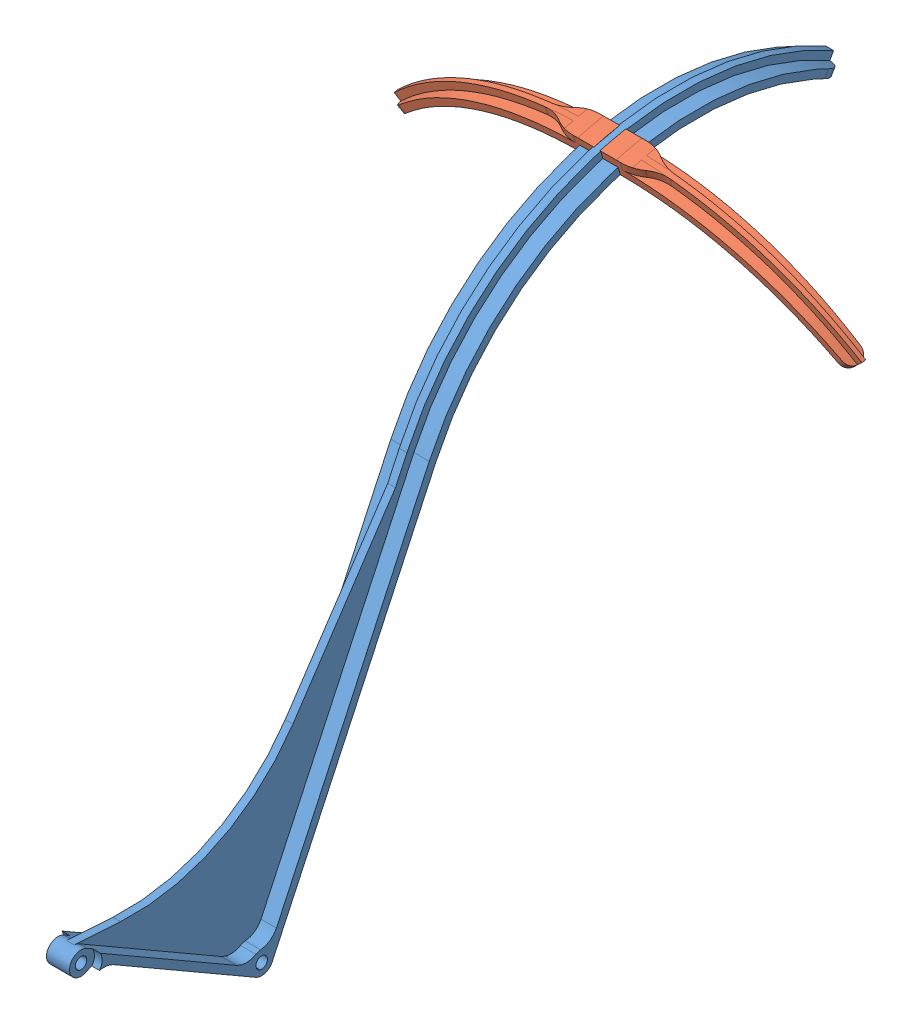
SolidWorks assembly BRACCETTOass, configuration Default. Lengths in mm.
Overall size (121.82 140.58 200.98).
3 component instances, 2 part files, 3 mates.
Components (placement in the parent):
- Braccetto2-1: Braccetto2 [Default] at (159.9586 -52.3434 25.7533) x (1 0 0) z (0 -1 0) size (10.64 200.98 140.58)
- Cazzetto-1: Cazzetto [Default] at (164.9586 6.237 -87.6267) x (1 0 0) z (0 -0.225584 0.974224) size (60.11 26.44 7.84)
- Cazzetto-2: Cazzetto [Default] at (164.9586 6.237 -87.6267) x (-1 0 0) z (0 0.225584 -0.974224) size (60.11 26.44 7.84)
Mates (geometry in assembly coordinates):
- Distanza1: distance = 0 mm anti-aligned: plane of Cazzetto-2 through (169.9586 6.237 -87.6267) normal (0 0.182874 -0.983136); plane of Braccetto2-1 through (165.7586 81.9385 -73.5454) normal (0 -0.182874 0.983136)
- Distanza2: distance = 0 mm anti-aligned: plane of Braccetto2-1 through (165.7586 6.237 -87.6267) normal (1 0 0); plane of Cazzetto-2 through (165.7586 83.2007 -69.8056) normal (-1 0 0)
- Distanza3: distance = 0 mm: cylinder of Cazzetto-2 through (164.9586 6.237 -87.6267) axis (-1 0 0) radius 77; cylinder of Braccetto2-1 through (169.9586 6.237 -87.6267) axis (-1 0 0) radius 77
